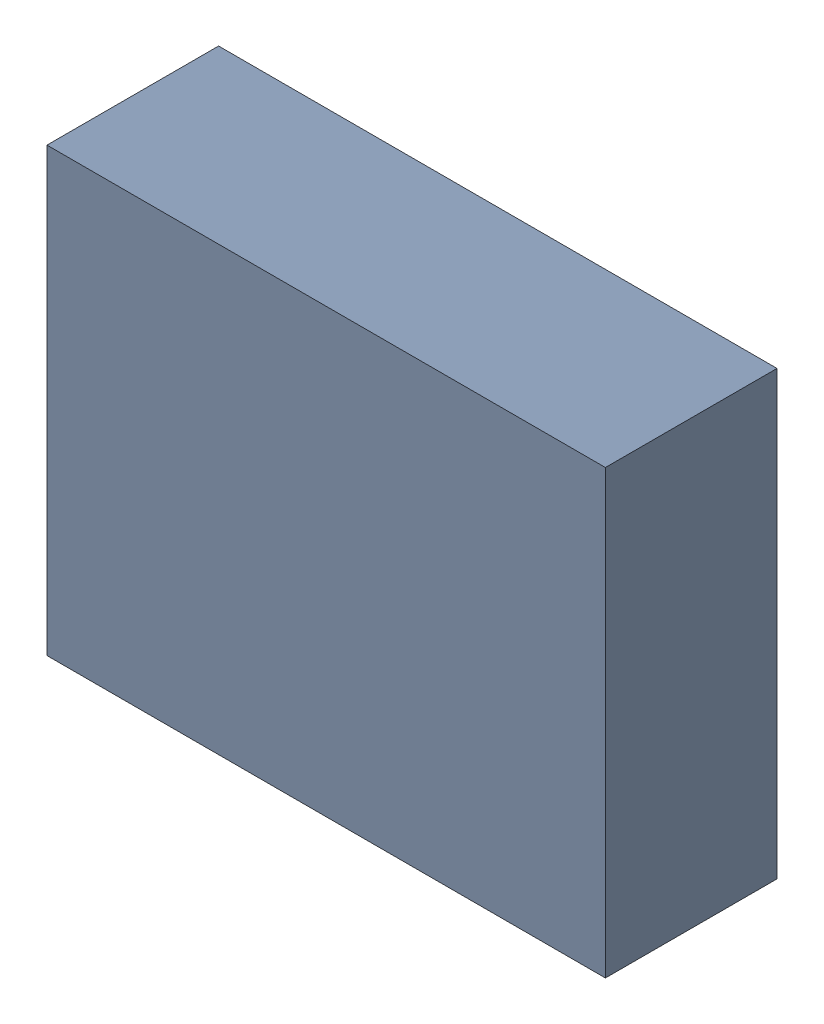
SolidWorks assembly OP1, configuration Default. Lengths in mm.
Overall size (5.04 3.99 1.55).
2 component instances, 1 part files, 0 mates.
Components (placement in the parent):
- 407985952-1: 407985952 [Default] at (55.245 65.913 0.2157) size (5.04 3.99 1.55)
  - Extruded-1: Extruded [Default] at origin size (5.04 3.99 1.55)
